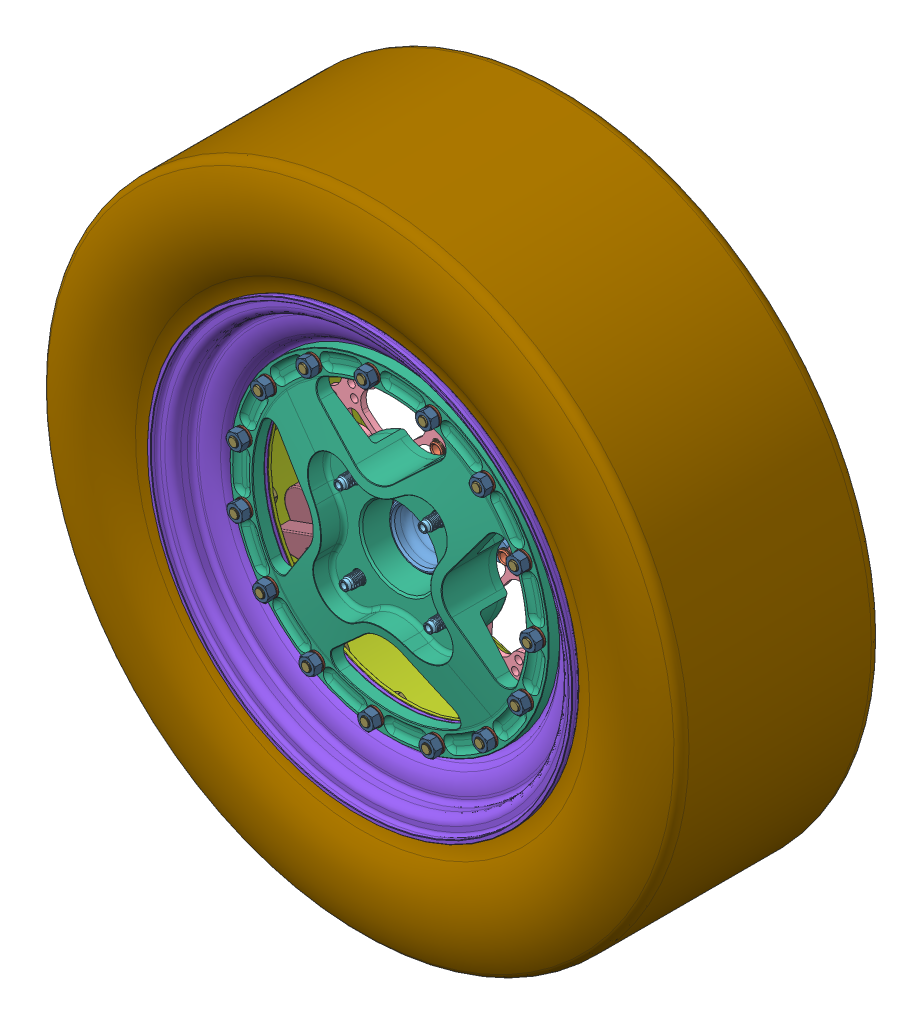
SolidWorks assembly Front Hub Assembly, configuration Default. Lengths in mm.
Overall size (752.77 752.77 186.83).
82 component instances, 19 part files, 19 mates.
Components (placement in the parent):
- Front Hub-1: Front Hub [Default] x (0 0 1) z (-0.751274 0.659991 0) size (87.74 117.35 117.35)
- Brake Rotor Pin-1: Brake Rotor Pin [Default] at (28.708 32.6785 90.932) x (0 0 1) z (-0.716729 0.697352 0) size (8.93 13.97 13.97)
- Brake Rotor Snap Ring-1: Brake Rotor Snap Ring [Default] at (28.708 32.6785 97.9551) x (0 0 1) z (-0.716729 0.697352 0) size (0.64 12.88 11.47)
- Brake Rotor-1: Brake Rotor [Default] at (0 0 92.202) x (0.751274 -0.659991 0) z (0 0 1) size (227.12 227.12 4.57)
- Brake Rotor Snap Ring-2: Brake Rotor Snap Ring [Default] at (42.6544 -8.5226 97.9551) x (0 0 1) z (0.24556 0.969381 0) size (0.64 12.88 11.47)
- Brake Rotor Snap Ring-3: Brake Rotor Snap Ring [Default] at (13.9464 -41.2011 97.9551) x (0 0 1) z (0.962289 0.27203 0) size (0.64 12.88 11.47)
- Brake Rotor Snap Ring-4: Brake Rotor Snap Ring [Default] at (-28.708 -32.6785 97.9551) x (0 0 1) z (0.716729 -0.697352 0) size (0.64 12.88 11.47)
- Brake Rotor Snap Ring-5: Brake Rotor Snap Ring [Default] at (-42.6544 8.5226 97.9551) x (0 0 1) z (-0.24556 -0.969381 0) size (0.64 12.88 11.47)
- Brake Rotor Snap Ring-6: Brake Rotor Snap Ring [Default] at (-13.9464 41.2011 97.9551) x (0 0 1) z (-0.962289 -0.27203 0) size (0.64 12.88 11.47)
- Brake Rotor Pin-2: Brake Rotor Pin [Default] at (42.6544 -8.5226 90.932) x (0 0 1) z (0.24556 0.969381 0) size (8.93 13.97 13.97)
- Brake Rotor Pin-3: Brake Rotor Pin [Default] at (13.9464 -41.2011 90.932) x (0 0 1) z (0.962289 0.27203 0) size (8.93 13.97 13.97)
- Brake Rotor Pin-4: Brake Rotor Pin [Default] at (-28.708 -32.6785 90.932) x (0 0 1) z (0.716729 -0.697352 0) size (8.93 13.97 13.97)
- Brake Rotor Pin-5: Brake Rotor Pin [Default] at (-42.6544 8.5226 90.932) x (0 0 1) z (-0.24556 -0.969381 0) size (8.93 13.97 13.97)
- Brake Rotor Pin-6: Brake Rotor Pin [Default] at (-13.9464 41.2011 90.932) x (0 0 1) z (-0.962289 -0.27203 0) size (8.93 13.97 13.97)
- Titanium Stud-1: Titanium Stud [Default] at (32.9995 37.5637 106.9975) x (0 0 1) z (-0.751274 0.659991 0) size (50.8 12.7 12.7)
- Titanium Stud-2: Titanium Stud [Default] at (37.5637 -32.9995 106.9975) x (0 0 1) z (0.659991 0.751274 0) size (50.8 12.7 12.7)
- Titanium Stud-3: Titanium Stud [Default] at (-32.9995 -37.5637 106.9975) x (0 0 1) z (0.751274 -0.659991 0) size (50.8 12.7 12.7)
- Titanium Stud-4: Titanium Stud [Default] at (-37.5637 32.9995 106.9975) x (0 0 1) z (-0.659991 -0.751274 0) size (50.8 12.7 12.7)
- Front Wheel-1: Front Wheel [Default] at (0.0001 0.0001 171.45) x (0.751274 -0.659991 0) z (0 0 1) size (533.4 533.4 185.42)
  - Front Center-1: Front Center [Default] at origin size (266.7 266.7 48.96)
  - Front Inner Rim-1: Front Inner Rim [Default] at (0 0 -31.75) x (0 0 -1) z (1 0 0) size (134.62 355.6 355.6)
  - Front Outer Rim-1: Front Outer Rim [Default] at (0 0 -31.75) size (355.6 355.6 37.46)
  - Front Tire-1: Front Tire [Default] at (0 0 -78.994) x (0 0 1) z (-1 0 0) size (185.42 533.4 533.4)
  - Steel Hex 5_16-18 Grade 5-1: Steel Hex 5_16-18 Grade 5 [95462A030] at (0 123.825 -13.9621) x (-0.923728 -0.383049 0) z (0 0 -1) size (12.7 14.66 8.63)
  - 5_16 Small OD Washer-1: 5_16 Small OD Washer [Default] at (0 123.825 -17.3355) x (1 0 0) z (0 1 0) size (14.22 1.72 14.22)
  - 5_16 Small OD Washer-17: 5_16 Small OD Washer [Default] at (50.3642 113.1198 -17.3355) x (0.913545 -0.406737 0) z (0.406737 0.913545 0) size (14.22 1.72 14.22)
  - 5_16 Small OD Washer-18: 5_16 Small OD Washer [Default] at (92.0199 82.8551 -17.3355) x (0.669131 -0.743145 0) z (0.743145 0.669131 0) size (14.22 1.72 14.22)
  - 5_16 Small OD Washer-19: 5_16 Small OD Washer [Default] at (117.7646 38.264 -17.3355) x (0.309017 -0.951057 0) z (0.951057 0.309017 0) size (14.22 1.72 14.22)
  - 5_16 Small OD Washer-20: 5_16 Small OD Washer [Default] at (123.1467 -12.9432 -17.3355) x (-0.104528 -0.994522 0) z (0.994522 -0.104528 0) size (14.22 1.72 14.22)
  - 5_16 Small OD Washer-21: 5_16 Small OD Washer [Default] at (107.2356 -61.9125 -17.3355) x (-0.5 -0.866025 0) z (0.866025 -0.5 0) size (14.22 1.72 14.22)
  - 5_16 Small OD Washer-22: 5_16 Small OD Washer [Default] at (72.7825 -100.1765 -17.3355) x (-0.809017 -0.587785 0) z (0.587785 -0.809017 0) size (14.22 1.72 14.22)
  - 5_16 Small OD Washer-23: 5_16 Small OD Washer [Default] at (25.7447 -121.1191 -17.3355) x (-0.978148 -0.207912 0) z (0.207912 -0.978148 0) size (14.22 1.72 14.22)
  - 5_16 Small OD Washer-24: 5_16 Small OD Washer [Default] at (-25.7447 -121.1191 -17.3355) x (-0.978148 0.207912 0) z (-0.207912 -0.978148 0) size (14.22 1.72 14.22)
  - 5_16 Small OD Washer-25: 5_16 Small OD Washer [Default] at (-72.7825 -100.1765 -17.3355) x (-0.809017 0.587785 0) z (-0.587785 -0.809017 0) size (14.22 1.72 14.22)
  - 5_16 Small OD Washer-26: 5_16 Small OD Washer [Default] at (-107.2356 -61.9125 -17.3355) x (-0.5 0.866025 0) z (-0.866025 -0.5 0) size (14.22 1.72 14.22)
  - 5_16 Small OD Washer-27: 5_16 Small OD Washer [Default] at (-123.1467 -12.9432 -17.3355) x (-0.104528 0.994522 0) z (-0.994522 -0.104528 0) size (14.22 1.72 14.22)
  - 5_16 Small OD Washer-28: 5_16 Small OD Washer [Default] at (-117.7646 38.264 -17.3355) x (0.309017 0.951057 0) z (-0.951057 0.309017 0) size (14.22 1.72 14.22)
  - 5_16 Small OD Washer-29: 5_16 Small OD Washer [Default] at (-92.0199 82.8551 -17.3355) x (0.669131 0.743145 0) z (-0.743145 0.669131 0) size (14.22 1.72 14.22)
  - 5_16 Small OD Washer-30: 5_16 Small OD Washer [Default] at (-50.3642 113.1198 -17.3355) x (0.913545 0.406737 0) z (-0.406737 0.913545 0) size (14.22 1.72 14.22)
  - Steel Hex 5_16-18 Grade 5-2: Steel Hex 5_16-18 Grade 5 [95462A030] at (50.3642 113.1198 -13.9621) x (-0.999668 0.025781 0) z (0 0 -1) size (12.7 14.66 8.63)
  - Steel Hex 5_16-18 Grade 5-3: Steel Hex 5_16-18 Grade 5 [95462A030] at (92.0199 82.8551 -13.9621) x (-0.902756 0.430154 0) z (0 0 -1) size (12.7 14.66 8.63)
  - Steel Hex 5_16-18 Grade 5-4: Steel Hex 5_16-18 Grade 5 [95462A030] at (117.7646 38.264 -13.9621) x (-0.649749 0.760149 0) z (0 0 -1) size (12.7 14.66 8.63)
  - Steel Hex 5_16-18 Grade 5-5: Steel Hex 5_16-18 Grade 5 [95462A030] at (123.1467 -12.9432 -13.9621) x (-0.284395 0.958707 0) z (0 0 -1) size (12.7 14.66 8.63)
  - Steel Hex 5_16-18 Grade 5-6: Steel Hex 5_16-18 Grade 5 [95462A030] at (107.2356 -61.9125 -13.9621) x (0.130134 0.991496 0) z (0 0 -1) size (12.7 14.66 8.63)
  - Steel Hex 5_16-18 Grade 5-7: Steel Hex 5_16-18 Grade 5 [95462A030] at (72.7825 -100.1765 -13.9621) x (0.522161 0.852847 0) z (0 0 -1) size (12.7 14.66 8.63)
  - Steel Hex 5_16-18 Grade 5-8: Steel Hex 5_16-18 Grade 5 [95462A030] at (25.7447 -121.1191 -13.9621) x (0.823902 0.566732 0) z (0 0 -1) size (12.7 14.66 8.63)
  - Steel Hex 5_16-18 Grade 5-9: Steel Hex 5_16-18 Grade 5 [95462A030] at (-25.7447 -121.1191 -13.9621) x (0.983183 0.182625 0) z (0 0 -1) size (12.7 14.66 8.63)
  - Steel Hex 5_16-18 Grade 5-10: Steel Hex 5_16-18 Grade 5 [95462A030] at (-72.7825 -100.1765 -13.9621) x (0.972462 -0.233061 0) z (0 0 -1) size (12.7 14.66 8.63)
  - Steel Hex 5_16-18 Grade 5-11: Steel Hex 5_16-18 Grade 5 [95462A030] at (-107.2356 -61.9125 -13.9621) x (0.793594 -0.608447 0) z (0 0 -1) size (12.7 14.66 8.63)
  - Steel Hex 5_16-18 Grade 5-12: Steel Hex 5_16-18 Grade 5 [95462A030] at (-123.1467 -12.9432 -13.9621) x (0.477506 -0.878628 0) z (0 0 -1) size (12.7 14.66 8.63)
  - Steel Hex 5_16-18 Grade 5-13: Steel Hex 5_16-18 Grade 5 [95462A030] at (-117.7646 38.264 -13.9621) x (0.078854 -0.996886 0) z (0 0 -1) size (12.7 14.66 8.63)
  - Steel Hex 5_16-18 Grade 5-14: Steel Hex 5_16-18 Grade 5 [95462A030] at (-92.0199 82.8551 -13.9621) x (-0.333434 -0.942774 0) z (0 0 -1) size (12.7 14.66 8.63)
  - Steel Hex 5_16-18 Grade 5-15: Steel Hex 5_16-18 Grade 5 [95462A030] at (-50.3642 113.1198 -13.9621) x (-0.688067 -0.725647 0) z (0 0 -1) size (12.7 14.66 8.63)
  - Steel 5_16in-18 1in Wheel-1: Steel 5_16in-18 1in Wheel [Default] at (0 123.825 -31.75) x (-1 0 0) z (0 0 -1) size (12.7 14.41 30.67)
  - Steel 5_16in-18 1in Wheel-2: Steel 5_16in-18 1in Wheel [Default] at (50.3642 113.1198 -31.75) x (-0.913545 0.406737 0) z (0 0 -1) size (12.7 14.41 30.67)
  - Steel 5_16in-18 1in Wheel-3: Steel 5_16in-18 1in Wheel [Default] at (92.0199 82.8551 -31.75) x (-0.669131 0.743145 0) z (0 0 -1) size (12.7 14.41 30.67)
  - Steel 5_16in-18 1in Wheel-4: Steel 5_16in-18 1in Wheel [Default] at (117.7646 38.264 -31.75) x (-0.309017 0.951057 0) z (0 0 -1) size (12.7 14.41 30.67)
  - Steel 5_16in-18 1in Wheel-5: Steel 5_16in-18 1in Wheel [Default] at (123.1467 -12.9432 -31.75) x (0.104528 0.994522 0) z (0 0 -1) size (12.7 14.41 30.67)
  - Steel 5_16in-18 1in Wheel-6: Steel 5_16in-18 1in Wheel [Default] at (107.2356 -61.9125 -31.75) x (0.5 0.866025 0) z (0 0 -1) size (12.7 14.41 30.67)
  - Steel 5_16in-18 1in Wheel-7: Steel 5_16in-18 1in Wheel [Default] at (72.7825 -100.1765 -31.75) x (0.809017 0.587785 0) z (0 0 -1) size (12.7 14.41 30.67)
  - Steel 5_16in-18 1in Wheel-8: Steel 5_16in-18 1in Wheel [Default] at (25.7447 -121.1191 -31.75) x (0.978148 0.207912 0) z (0 0 -1) size (12.7 14.41 30.67)
  - Steel 5_16in-18 1in Wheel-9: Steel 5_16in-18 1in Wheel [Default] at (-25.7447 -121.1191 -31.75) x (0.978148 -0.207912 0) z (0 0 -1) size (12.7 14.41 30.67)
  - Steel 5_16in-18 1in Wheel-10: Steel 5_16in-18 1in Wheel [Default] at (-72.7825 -100.1765 -31.75) x (0.809017 -0.587785 0) z (0 0 -1) size (12.7 14.41 30.67)
  - Steel 5_16in-18 1in Wheel-11: Steel 5_16in-18 1in Wheel [Default] at (-107.2356 -61.9125 -31.75) x (0.5 -0.866025 0) z (0 0 -1) size (12.7 14.41 30.67)
  - Steel 5_16in-18 1in Wheel-12: Steel 5_16in-18 1in Wheel [Default] at (-123.1467 -12.9432 -31.75) x (0.104528 -0.994522 0) z (0 0 -1) size (12.7 14.41 30.67)
  - Steel 5_16in-18 1in Wheel-13: Steel 5_16in-18 1in Wheel [Default] at (-117.7646 38.264 -31.75) x (-0.309017 -0.951057 0) z (0 0 -1) size (12.7 14.41 30.67)
  - Steel 5_16in-18 1in Wheel-14: Steel 5_16in-18 1in Wheel [Default] at (-92.0199 82.8551 -31.75) x (-0.669131 -0.743145 0) z (0 0 -1) size (12.7 14.41 30.67)
  - Steel 5_16in-18 1in Wheel-15: Steel 5_16in-18 1in Wheel [Default] at (-50.3642 113.1198 -31.75) x (-0.913545 -0.406737 0) z (0 0 -1) size (12.7 14.41 30.67)
- Brake Caliper-1: Brake Caliper [Default] at (-56.5984 -73.0606 73.1785) x (0.612707 -0.79031 0) z (0 0 -1) size (101.75 67.09 67.01)
  - Brake Caliper Frame-1: Brake Caliper Frame [Default] at origin size (101.75 67.09 67.01)
  - Brake Pad-1: Brake Pad [Default] at (-23.5554 37.6919 -13.7004) x (0.999992 0.003877 0) z (0 0 1) size (67.93 44.48 7.61)
  - Brake Pad-2: Brake Pad [Default] at (-23.5554 37.6919 -29.2996) x (-0.999992 -0.003877 0) z (0 0 -1) size (67.93 44.48 7.61)
  - Brake Pin-1: Brake Pin [Default] at (-23.5554 37.6919 -26.0423) x (0 0 1) z (0.999547 0.030097 0) size (39.8 8.85 8.85)
- Front Upright Bearing-1: Front Upright Bearing [Default] at (0 0 71.4007) x (0 0 1) z (-0.993366 0.114998 0) size (15.08 64.99 62.93) (flexible)
  - Front Cup-1: Front Cup [Default] at origin size (10.72 58.74 58.74)
  - Front Cone-1: Front Cone [Default] x (1 0 0) z (0 -0.968239 -0.250025) size (15.08 45.11 45.11)
  - Front Rollers-1: Front Rollers [Default] x (1 0 0) z (0 -0.968239 -0.250025) size (11.17 53.47 53.31)
- Front Upright Bearing-2: Front Upright Bearing [Default] at (0 0 26.9961) x (0 0 -1) z (0.839252 0.543743 0) size (15.08 69.76 69.41) (flexible)
  - Front Cup-1: Front Cup [Default] at origin size (10.72 58.74 58.74)
  - Front Cone-1: Front Cone [Default] x (1 0 0) z (0 0.774216 -0.632921) size (15.08 45.11 45.11)
  - Front Rollers-1: Front Rollers [Default] x (1 0 0) z (0 0.774216 -0.632921) size (11.17 53.47 53.31)
- Front Hub Nut-1: Front Hub Nut [Default] at (0 0 -0.7838) x (0.75957 -0.650425 0) z (0 0 1) size (44.45 44.45 14.47)
Mates (geometry in assembly coordinates):
- Concentric1: concentric aligned: cylinder of Front Hub-1 through (28.708 32.6785 102.997) axis (0 0 -1) radius 5.3975; cylinder of Brake Rotor Pin-1 through (28.708 32.6785 90.932) axis (0 0 -1) radius 5.3721
- Concentric2: concentric aligned: cylinder of Front Hub-1 through (28.708 32.6785 102.997) axis (0 0 -1) radius 5.3975; cylinder of Brake Rotor Snap Ring-1 through (28.708 32.6785 98.2726) axis (0 0 -1) radius 4.6482
- Coincident4: coincident anti-aligned: plane of Brake Rotor Pin-1 through (32.0911 36.1557 98.2726) normal (0 0 -1); plane of Brake Rotor Snap Ring-1 through (28.708 32.6785 98.2726) normal (0 0 1)
- Concentric3: concentric aligned: cylinder of Brake Rotor Pin-1 through (28.708 32.6785 90.932) axis (0 0 -1) radius 5.3721; cylinder of Brake Rotor-1 through (28.708 32.6785 96.774) axis (0 0 -1) radius 5.4356
- Concentric4: concentric aligned: cylinder of Front Hub-1 through (42.6544 -8.5226 102.997) axis (0 0 -1) radius 5.3975; cylinder of Brake Rotor-1 through (42.6544 -8.5226 96.774) axis (0 0 -1) radius 5.4356
- Concentric5: concentric anti-aligned: cylinder of Front Hub-1 through (32.9995 37.5637 106.045) axis (0 0 1) radius 5.3975; cylinder of Titanium Stud-1 through (32.9995 37.5637 106.9975) axis (0 0 -1) radius 5.3975
- Coincident8: coincident anti-aligned: plane of Front Hub-1 through (15.0874 17.1741 108.585) normal (0 0 -1); plane of Titanium Stud-1 through (37.1905 42.3343 108.585) normal (0 0 1)
- Concentric6: concentric aligned: cylinder of Front Hub-1 through (0 0 0) axis (0 0 -1) radius 15.875; cylinder of Front Wheel-1/Front Tire-1 through (0.0001 0.0001 69.2773) axis (0 0 -1) radius 266.7
- Concentric7: concentric aligned: cylinder of Titanium Stud-1 through (32.9995 37.5637 106.9975) axis (0 0 -1) radius 2.3813; cylinder of Front Wheel-1/Front Center-1 through (32.9995 37.5637 165.5797) axis (0 0 -1) radius 5.08
- Coincident10: coincident anti-aligned: plane of Front Hub-1; plane of Brake Caliper-1/Brake Caliper Frame-1 through (-56.5984 -73.0606 94.6785) normal (0 0 1)
- Coincident11: coincident anti-aligned: plane of Front Hub-1 through (38.7243 44.0802 116.84) normal (0 0 1); plane of Front Wheel-1/Front Center-1 through (0.0001 0.0001 116.84) normal (0 0 -1)
- Concentric8: concentric anti-aligned: circle of Brake Rotor-1; circle of Brake Caliper-1/Brake Pad-1
- Concentric9: concentric aligned: cylinder of Front Hub-1 through (0 0 0) axis (0 0 -1) radius 15.875; cylinder of Front Upright Bearing-1/Front Cone-1 through (0 0 72.5371) axis (0 0 -1) radius 19.9867
- Concentric10: concentric anti-aligned: cylinder of Front Hub-1 through (0 0 0) axis (0 0 -1) radius 15.875; cylinder of ? through (0 0 13.4687) axis (0 0 1) radius 22.5563
- Concentric11: concentric aligned: cylinder of Front Hub-1 through (0 0 0) axis (0 0 -1) radius 15.875; cylinder of Front Hub Nut-1 through (0 0 11.9162) axis (0 0 -1) radius 22.225
- Coincident12: coincident anti-aligned: plane of ? through (-18.78 6.0279 11.9162) normal (0 0 -1); plane of Front Hub Nut-1 through (0 0 11.9162) normal (0 0 1)
- Coincident13: coincident anti-aligned: plane of Front Hub-1 through (12.1118 13.787 86.4807) normal (0 0 -1); plane of Front Upright Bearing-1/Front Cone-1 through (2.7026 -19.5376 86.4807) normal (0 0 1)
- Coincident14: coincident anti-aligned: plane of Front Hub-1 through (15.0455 17.1264 92.202) normal (0 0 -1); plane of Brake Rotor Pin-1 through (33.579 37.6849 92.202) normal (0 0 1)
- Coincident16: coincident anti-aligned: plane of Brake Rotor Pin-1 through (33.579 37.6849 92.202) normal (0 0 1); plane of Brake Rotor-1 through (0 0 92.202) normal (0 0 -1)
